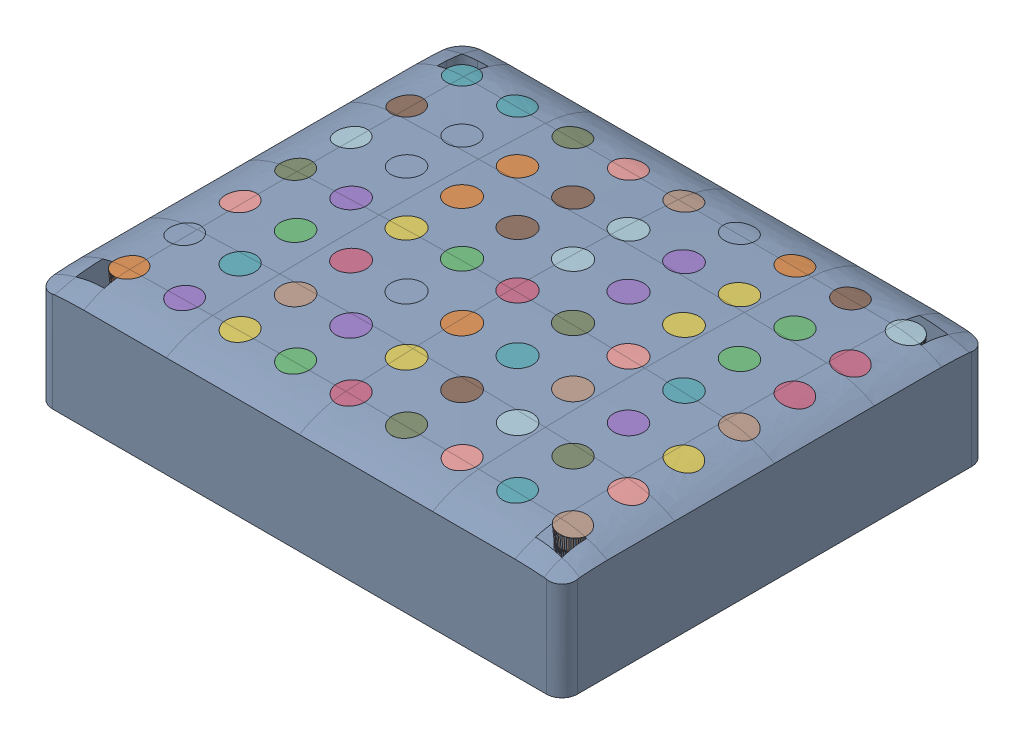
SolidWorks assembly mid, configuration 默认. Lengths in mm.
Overall size (23.8 5.49 19.29).
3 component instances, 3 part files, 4 mates.
Components (placement in the parent):
- Pin1InsideSkin-1: Pin1InsideSkin [默认] at origin size (23.8 5.49 19.29)
- Pin1markerTopTip-1: Pin1markerTopTip [默认] at (-10.075 23 6.925) x (1 0 0) z (0 1 0) size (21.2 16.2 0.4)
- Pin1Pinmarker1mm_1-1: Pin1Pinmarker1mm_1 [默认] at origin size (21.42 1.09 16.41)
Mates (geometry in assembly coordinates):
- 重合2: coordinate: point of Pin1Pinmarker1mm_1-1
- 重合4: coordinate: unknown of Pin1InsideSkin-1
- 重合5: coincident anti-aligned: plane of Pin1markerTopTip-1 through (-10.075 23.4 -8.075) normal (0 1 0); plane of Pin1Pinmarker1mm_1-1 through (-10.075 23.4 -8.075) normal (0 -1 0)
- 同心1: concentric aligned: cylinder of Pin1markerTopTip-1 through (-10.075 23.4 -8.075) axis (0 -1 0) radius 0.6; cone of Pin1Pinmarker1mm_1-1 through (-10.075 23.4 -8.075) axis (0 -1 0)
